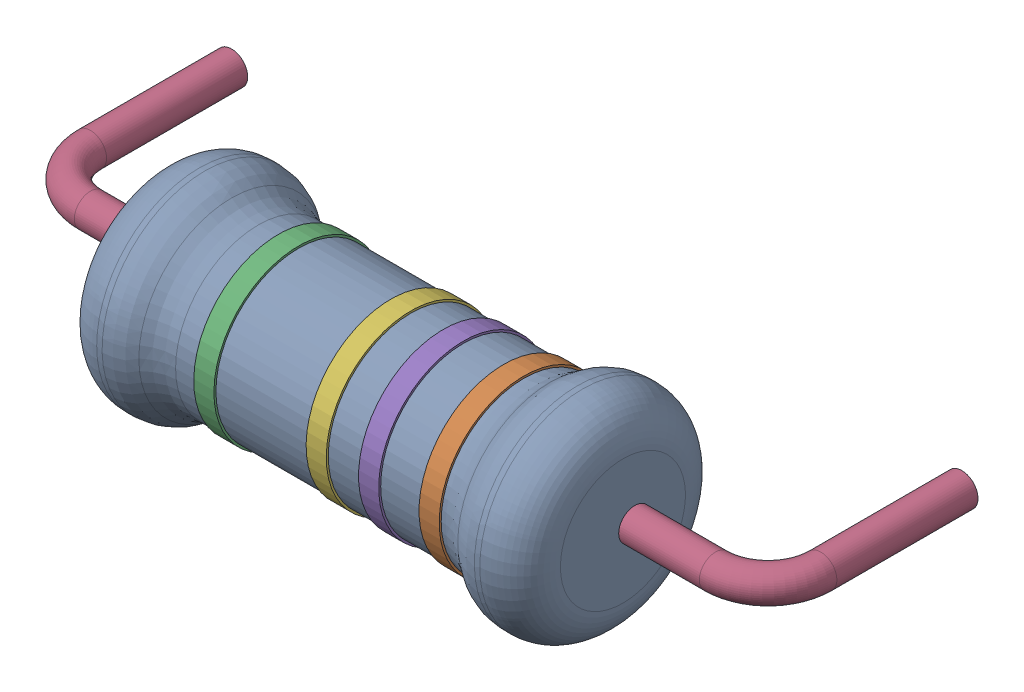
SolidWorks assembly R61.step, configuration Default. Lengths in mm.
Overall size (18.91 5.72 7.96).
7 component instances, 6 part files, 0 mates.
Components (placement in the parent):
- Res_Yageo_KNP100JR-73-22R_eec.step-1: Res_Yageo_KNP100JR-73-22R_eec.step [Default] at (64.389 10.414 0) x (-1 0 0) z (0 0 1) size (18.91 5.72 7.96)
  - 1.step-1: 1.step [Default] at (0 0 2.55) size (11.5 5.1 5.1)
  - 2.step-1: 2.step [Default] at (-3.2931 0 2.55) x (0 0 -1) z (1 0 0) size (4.2 4.2 0.5)
  - 3.step-1: 3.step [Default] at (2.7931 0 2.55) x (0 -0.492137 0.870518) z (-1 0 0) size (4.2 4.2 0.5)
  - 4.step-1: 4.step [Default] at (0 0 -2.55) size (18.91 0.8 5.21)
  - 5.step-1: 5.step [Default] at (-1.7931 0 2.55) x (0 0 -1) z (1 0 0) size (4.2 4.2 0.5)
  - 6.step-1: 6.step [Default] at (0.0069 0 2.55) x (0 -0.017206 0.999852) z (-1 0 0) size (4.2 4.2 0.5)
